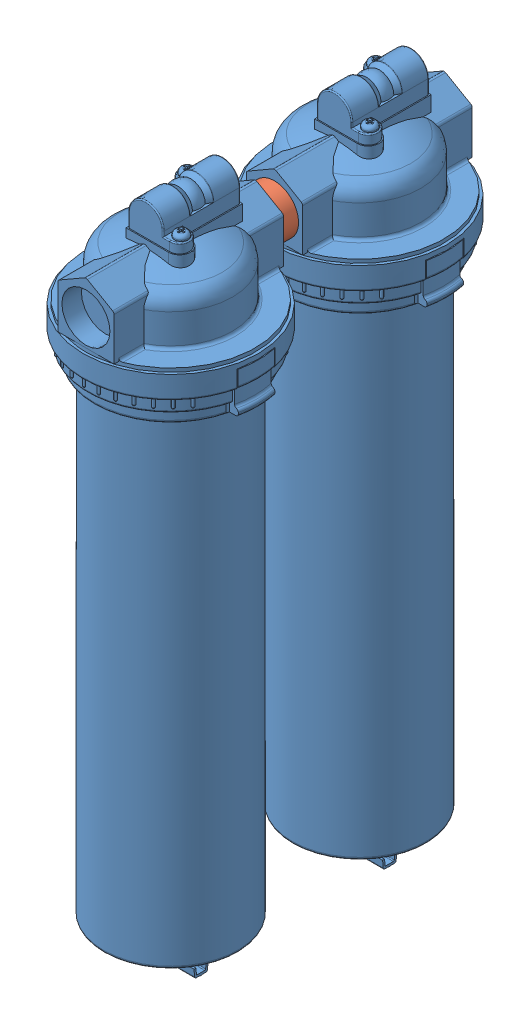
SolidWorks assembly ReadingTech_4P-150-M08-DCPi, configuration Default. Lengths in mm.
Overall size (121.86 464.6 252.73).
3 component instances, 2 part files, 3 mates.
Components (placement in the parent):
- ReadingTech_3P-150-M08-Pi-1: ReadingTech_3P-150-M08-Pi [Default] at (-14.5651 -187.0467 -5.1637) size (121.86 464.6 121.67)
- ReadingTech_3P-150-M08-Pi-2: ReadingTech_3P-150-M08-Pi [Default] at (-14.5651 -187.0467 -136.2277) size (121.86 464.6 121.67)
- ReadingTech- 90,150cfm_connector_1in-1: ReadingTech- 90,150cfm_connector_1in [Default] at (-14.5651 201.9543 -64.0917) x (1 0 0) z (0 1 0) size (33.4 13.21 33.4)
Mates (geometry in assembly coordinates):
- Coincident1: coincident anti-aligned: circle of ReadingTech_3P-150-M08-Pi-2; circle of ReadingTech- 90,150cfm_connector_1in-1
- Coincident2: coincident aligned: circle of ReadingTech_3P-150-M08-Pi-1; circle of ReadingTech- 90,150cfm_connector_1in-1
- Coincident3: coincident aligned: plane of ReadingTech_3P-150-M08-Pi-1 through (4.9929 214.6543 53.7643) normal (1 0 0); plane of ReadingTech_3P-150-M08-Pi-2 through (4.9929 214.6543 -77.2997) normal (1 0 0)
